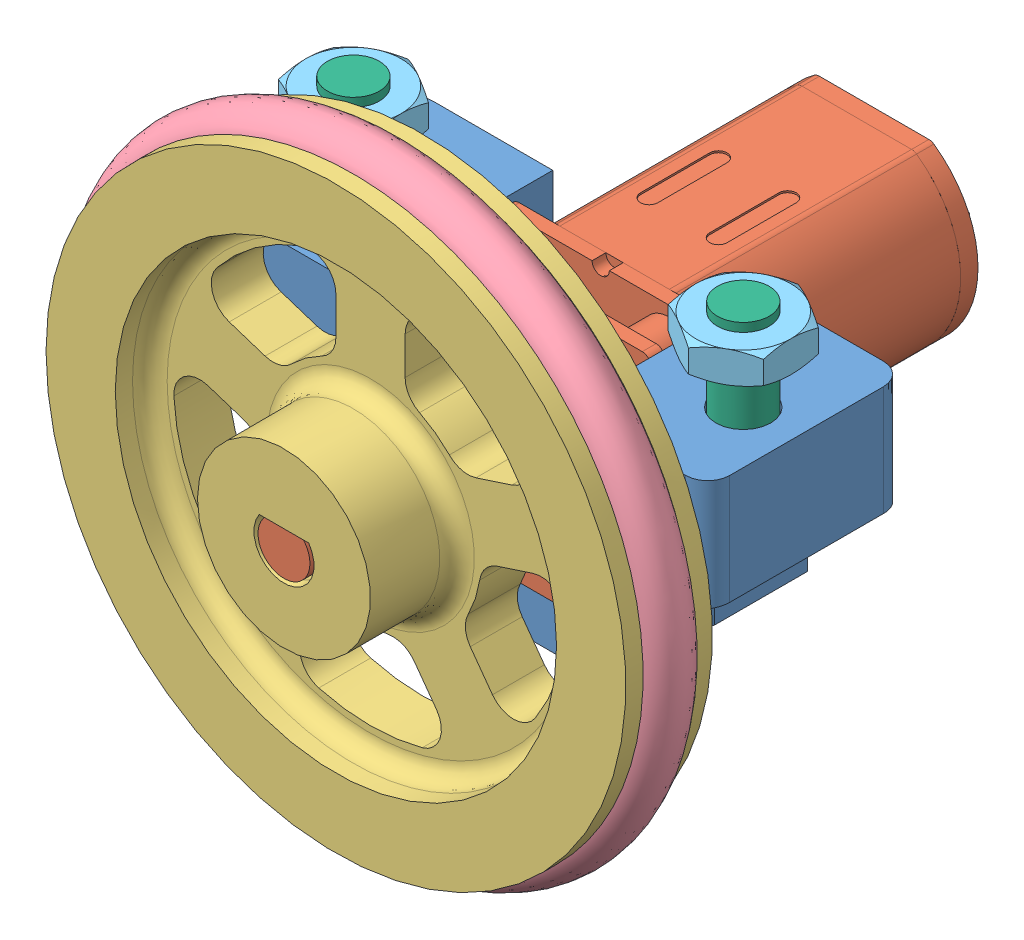
SolidWorks assembly Assembly wiel, configuration Default. Lengths in mm.
Overall size (35.5 35.5 35.9).
8 component instances, 6 part files, 23 mates.
Components (placement in the parent):
- Motor mount-1: Motor mount [Default] at (0 0 -17.78) x (1 0 0) z (0 0 -1) size (28.57 12.7 11.43)
- Micro Metal Gear Motor-1: Micro Metal Gear Motor [Default] at (-0.096 -5.16 -3.92) size (12 10 35.9)
- Wiel 29.5 x 3-1: Wiel 29.5 x 3 [Default] at (-0.096 -5.16 9.68) x (-1 0 0) z (0 0 -1) size (33.5 33.5 8)
- O-ring 29.5 x 3-1: O-ring 29.5 x 3 [Default] at (-0.096 -5.16 9.68) size (35.5 35.5 3)
- hex thin nut chamfered gradeab_iso-1: hex thin nut chamfered gradeab_iso [ISO - 4035 - M3 - N] at (-11.2625 4.8 0) x (1 0 0) z (0 1 0) size (5.5 6.35 1.8)
- hex thin nut chamfered gradeab_iso-2: hex thin nut chamfered gradeab_iso [ISO - 4035 - M3 - N] at (11.2625 4.8 0) x (-0.5 0 -0.866025) z (0 1 0) size (5.5 6.35 1.8)
- pan head cross recess screw_iso-1: pan head cross recess screw_iso [ISO 7045 - M3 x 10 - Z - 10N] at (-11.2625 -7.1 0) x (0 1 0) z (-1 0 0) size (12.35 5.6 5.6)
- pan head cross recess screw_iso-2: pan head cross recess screw_iso [ISO 7045 - M3 x 10 - Z - 10N] at (11.2625 -7.1 0) x (0 1 0) z (-1 0 0) size (12.35 5.6 5.6)
Mates (geometry in assembly coordinates):
- Coincident6: coincident aligned: plane of Motor mount-1 through (14.2875 0 5.08) normal (0 1 0)
- Coincident8: coincident aligned: plane of Motor mount-1 through (0 0 -17.78) normal (1 0 0)
- Coincident10: coincident anti-aligned: plane of Motor mount-1 through (-6.096 -10.16 5.08) normal (0 1 0); plane of Micro Metal Gear Motor-1 through (5.404 -10.16 4.28) normal (0 -1 0)
- Coincident11: coincident anti-aligned: plane of Motor mount-1 through (-6.096 -10.16 5.08) normal (1 0 0); plane of Micro Metal Gear Motor-1 through (-6.096 -9.66 4.28) normal (-1 0 0)
- Coincident12: coincident aligned: plane of Motor mount-1 through (0 0 5.08) normal (0 0 1); plane of Micro Metal Gear Motor-1 through (-5.596 -9.66 5.08) normal (0 0 1)
- Concentric5: concentric anti-aligned: cylinder of Micro Metal Gear Motor-1 through (-0.096 -5.16 15.18) axis (0 0 -1) radius 1.5; cylinder of Wiel 29.5 x 3-1 through (-0.096 -5.16 7.18) axis (0 0 1) radius 1.65
- Parallel6: parallel anti-aligned: plane of Micro Metal Gear Motor-1 through (-6.096 -4.16 15.18) normal (0 1 0); plane of Wiel 29.5 x 3-1 through (1.2869 -4.26 7.18) normal (0 -1 0)
- Coincident15: coincident aligned: plane of Micro Metal Gear Motor-1 through (-0.096 -5.16 15.18) normal (0 0 1); plane of Wiel 29.5 x 3-1 through (-0.096 -5.16 15.18) normal (0 0 1)
- Concentric6: concentric anti-aligned: cylinder of Wiel 29.5 x 3-1 through (-0.096 -5.16 15.18) axis (0 0 -1) radius 5; line of O-ring 29.5 x 3-1 through (-0.096 -5.16 8.03) axis (0 0 1)
- Parallel7: parallel aligned: plane of O-ring 29.5 x 3-1 through (-0.096 -22.91 9.68) normal (0 1 0)
- Coincident17: coincident anti-aligned: plane of Wiel 29.5 x 3-1 through (-0.096 -5.16 9.68) normal (0 0 -1); plane of O-ring 29.5 x 3-1 through (-0.096 -5.16 9.68) normal (0 0 1)
- Coincident18: coincident aligned: plane of hex thin nut chamfered gradeab_iso-1 through (-11.2625 4.8 -3.1754) normal (0 1 0); plane of hex thin nut chamfered gradeab_iso-2 through (8.5125 4.8 1.5877) normal (0 1 0)
- Coincident22: coincident aligned: plane of pan head cross recess screw_iso-1 through (-10.735 -5.35 0.37) normal (0 0 -1); plane of pan head cross recess screw_iso-2 through (11.79 -5.35 0.37) normal (0 0 -1)
- Coincident23: coincident aligned: plane of pan head cross recess screw_iso-1 through (-11.2625 -4.7 -1.5) normal (0 1 0); plane of pan head cross recess screw_iso-2 through (11.2625 -4.7 -1.5) normal (0 1 0)
- Concentric11: concentric aligned: cylinder of Motor mount-1 through (11.2625 1.27 0) axis (0 -1 0) radius 1.5875; cylinder of pan head cross recess screw_iso-2 through (11.2625 -32.5 0) axis (0 -1 0) radius 1.5
- Concentric12: concentric aligned: cylinder of Motor mount-1 through (-11.2625 1.27 0) axis (0 -1 0) radius 1.5875; cylinder of pan head cross recess screw_iso-1 through (-11.2625 -32.5 0) axis (0 -1 0) radius 1.5
- Parallel8: parallel anti-aligned: plane of Motor mount-1 through (14.2875 -6.35 5.08) normal (1 0 0); plane of hex thin nut chamfered gradeab_iso-2 through (8.5125 3 -1.5877) normal (-1 0 0)
- Concentric13: concentric anti-aligned: cylinder of hex thin nut chamfered gradeab_iso-2 through (11.2625 3 0) axis (0 1 0) radius 1.25; cylinder of pan head cross recess screw_iso-2 through (11.2625 -32.5 0) axis (0 -1 0) radius 1.5
- Concentric14: concentric anti-aligned: cylinder of hex thin nut chamfered gradeab_iso-1 through (-11.2625 3 0) axis (0 1 0) radius 1.25; cylinder of pan head cross recess screw_iso-1 through (-11.2625 -32.5 0) axis (0 -1 0) radius 1.5
- Coincident28: coincident: point of pan head cross recess screw_iso-2
- Parallel9: parallel aligned: plane of hex thin nut chamfered gradeab_iso-1 through (-14.0125 3 -1.5877) normal (-1 0 0); plane of hex thin nut chamfered gradeab_iso-2 through (8.5125 3 -1.5877) normal (-1 0 0)
- Coincident29: coincident anti-aligned: plane of Motor mount-1 through (11.2625 -4.7 0) normal (0 -1 0); plane of pan head cross recess screw_iso-2 through (11.2625 -4.7 -1.5) normal (0 1 0)
- Distance1: distance = 3 mm anti-aligned: plane of Motor mount-1 through (14.2875 0 5.08) normal (0 1 0); plane of hex thin nut chamfered gradeab_iso-2 through (8.5125 3 1.5877) normal (0 -1 0)
